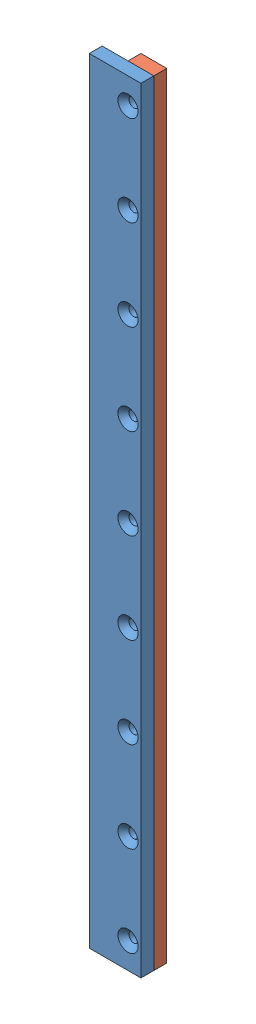
SolidWorks assembly Assem6, configuration Default. Lengths in mm.
Overall size (50.8 762 25.4).
2 component instances, 2 part files, 10 mates.
Components (placement in the parent):
- Wedge Mk2 Guide Rail-1: Wedge Mk2 Guide Rail [Default] at (134.6238 407.2911 657.4053) size (50.8 762 12.7)
- Wedge Mk2 Guide Rail Spacer-1: Wedge Mk2 Guide Rail Spacer [Default] at (147.3238 407.2911 644.7053) size (25.4 762 12.7)
Mates (geometry in assembly coordinates):
- Concentric1: concentric aligned: cylinder of Wedge Mk2 Guide Rail-1 through (147.3238 762.8911 663.7553) axis (0 0 1) radius 4.9022; cylinder of Wedge Mk2 Guide Rail Spacer-1 through (147.3238 762.8911 651.0553) axis (0 0 1) radius 4.7625
- Concentric2: concentric aligned: cylinder of Wedge Mk2 Guide Rail-1 through (147.3238 673.9911 663.7553) axis (0 0 1) radius 4.9022; cylinder of Wedge Mk2 Guide Rail Spacer-1 through (147.3238 673.9911 651.0553) axis (0 0 1) radius 4.7625
- Concentric3: concentric aligned: cylinder of Wedge Mk2 Guide Rail-1 through (147.3238 585.0911 663.7553) axis (0 0 1) radius 4.9022; cylinder of Wedge Mk2 Guide Rail Spacer-1 through (147.3238 585.0911 651.0553) axis (0 0 1) radius 4.7625
- Concentric4: concentric aligned: cylinder of Wedge Mk2 Guide Rail-1 through (147.3238 496.1911 663.7553) axis (0 0 1) radius 4.9022; cylinder of Wedge Mk2 Guide Rail Spacer-1 through (147.3238 496.1911 651.0553) axis (0 0 1) radius 4.7625
- Concentric5: concentric aligned: cylinder of Wedge Mk2 Guide Rail-1 through (147.3238 407.2911 663.7553) axis (0 0 1) radius 4.9022; cylinder of Wedge Mk2 Guide Rail Spacer-1 through (147.3238 407.2911 651.0553) axis (0 0 1) radius 4.7625
- Concentric6: concentric aligned: cylinder of Wedge Mk2 Guide Rail-1 through (147.3238 318.3911 663.7553) axis (0 0 1) radius 4.9022; cylinder of Wedge Mk2 Guide Rail Spacer-1 through (147.3238 318.3911 651.0553) axis (0 0 1) radius 4.7625
- Concentric7: concentric aligned: cylinder of Wedge Mk2 Guide Rail-1 through (147.3238 229.4911 663.7553) axis (0 0 1) radius 4.9022; cylinder of Wedge Mk2 Guide Rail Spacer-1 through (147.3238 229.4911 651.0553) axis (0 0 1) radius 4.7625
- Concentric8: concentric aligned: cylinder of Wedge Mk2 Guide Rail-1 through (147.3238 140.5911 663.7553) axis (0 0 1) radius 4.9022; cylinder of Wedge Mk2 Guide Rail Spacer-1 through (147.3238 140.5911 651.0553) axis (0 0 1) radius 4.7625
- Concentric9: concentric aligned: cylinder of Wedge Mk2 Guide Rail-1 through (147.3238 51.6911 663.7553) axis (0 0 1) radius 4.9022; cylinder of Wedge Mk2 Guide Rail Spacer-1 through (147.3238 51.6911 651.0553) axis (0 0 1) radius 4.7625
- Coincident1: coincident anti-aligned: plane of Wedge Mk2 Guide Rail-1 through (134.6238 407.2911 651.0553) normal (0 0 -1); plane of Wedge Mk2 Guide Rail Spacer-1 through (147.3238 407.2911 651.0553) normal (0 0 1)
